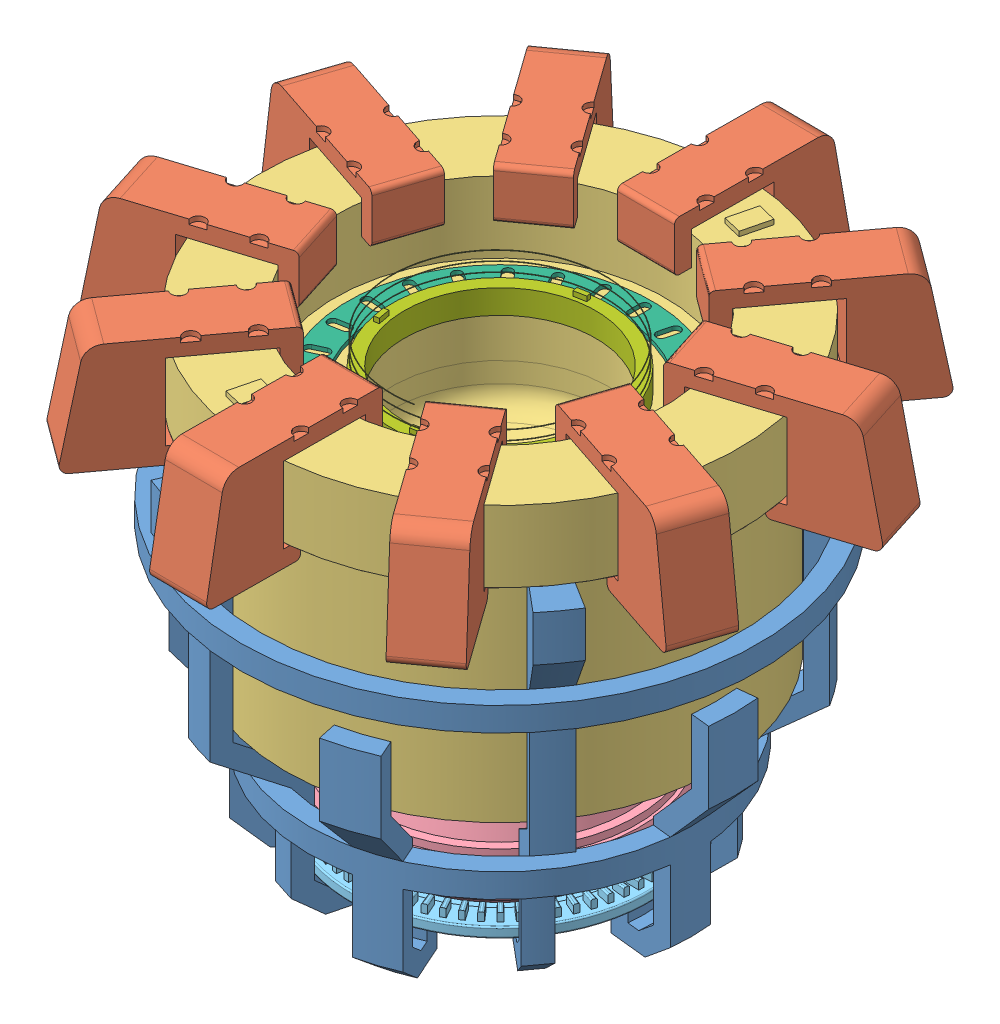
SolidWorks assembly TheArcReactor, configuration Default. Lengths in mm.
Overall size (168.05 102.8 166.25).
7 component instances, 7 part files, 16 mates.
Components (placement in the parent):
- Base-1: Base [Default] at origin size (133.9 83.07 126.71)
- ParticleAcceleratorModule-1: ParticleAcceleratorModule [Default] at (0 28.3999 0) x (-0.948876 0 -0.315649) z (0.315649 0 -0.948876) size (133.6 49.11 130.77)
- ReactonChamber-1: ReactonChamber [Default] at (0 -17.7 0) x (0.970296 0 0.241922) z (-0.241922 0 0.970296) size (99.78 62 99.78)
- ControlModule-1: ControlModule [Default] at (0 -37.5 0) x (-0.766044 0 0.642788) z (-0.642788 0 -0.766044) size (60 29.8 60)
- HeatSink-1: HeatSink [Default] at (0 -47.5 0) x (0.900552 0 -0.434748) z (0.434748 0 0.900552) size (62.2 4.49 62.2)
- TopCollar-1: TopCollar [Default] at (0 28.3 0) x (-0.766044 0 -0.642788) z (0.642788 0 -0.766044) size (63.54 0.85 63.54)
- Supporter-1: Supporter [Default] at (0 28.3 0) x (0.983571 0 -0.180519) z (0.180519 0 0.983571) size (47 11.05 46.2)
Mates (geometry in assembly coordinates):
- Concentric1: concentric aligned: cylinder of Base-1 through (0 15.0256 0) axis (0 1 0) radius 36; cylinder of HeatSink-1 through (0 202.4038 0) axis (0 1 0) radius 31.1
- Concentric5: concentric aligned: cylinder of Base-1 through (0 15.0256 0) axis (0 1 0) radius 50; cylinder of ReactonChamber-1 through (0 -112.8102 0) axis (0 1 0) radius 49.89
- Coincident17: coincident anti-aligned: circle of ParticleAcceleratorModule-1; circle of ReactonChamber-1
- Coincident18: coincident anti-aligned: plane of ReactonChamber-1 through (0 28.3 0) normal (0 1 0); plane of TopCollar-1 through (0 28.3 0) normal (0 -1 0)
- Concentric6: concentric anti-aligned: cylinder of ReactonChamber-1 through (0 -112.8102 0) axis (0 1 0) radius 34.5; cylinder of TopCollar-1 through (0 29.15 0) axis (0 -1 0) radius 31.77
- Tangent12: tangent anti-aligned: plane of Base-1 through (16.8846 -49 -14.1678) normal (0 1 0); torus of HeatSink-1
- Parallel9: parallel aligned: plane of ParticleAcceleratorModule-1 through (-31.5937 38.2999 -4.1866) normal (-0.315649 0 0.948876); plane of TopCollar-1 through (-28.1696 28.3 -10.4247) normal (-0.315649 0 0.948876)
- Concentric12: concentric aligned: cylinder of Base-1 through (0 15.0256 0) axis (0 1 0) radius 36; cone of ControlModule-1 through (0 -35.5 0) axis (0 1 0)
- Coincident32: coincident anti-aligned: plane of ControlModule-1 through (0 -47.5 0) normal (0 -1 0); plane of HeatSink-1 through (-23.0541 -47.5 11.1295) normal (0 1 0)
- Coincident33: coincident anti-aligned: plane of ReactonChamber-1 through (0 -17.7 0) normal (0 -1 0); plane of ControlModule-1 through (0 -17.7 0) normal (0 1 0)
- Parallel11: parallel aligned: plane of Base-1 through (0 0 0) normal (0.669131 0 0.743145); plane of HeatSink-1 through (0 -44.53 0) normal (0.669131 0 0.743145)
- Parallel14: parallel aligned: plane of Base-1 through (0 0 0) normal (-0.642788 0 -0.766044); plane of ControlModule-1 through (14.2951 -26.5 -13.3004) normal (-0.642788 0 -0.766044)
- Parallel17: parallel anti-aligned: plane of Base-1 through (0 0 0) normal (0.529919 0 0.848048); plane of TopCollar-1 through (25.9883 28.3 -15.0601) normal (-0.529919 0 -0.848048)
- Parallel19: parallel aligned: plane of Base-1 through (0 0 0) normal (0.970296 0 0.241922); plane of ReactonChamber-1 through (-7.7363 44.3 39.2957) normal (0.970296 0 0.241922)
- Coincident34: coincident aligned: circle of ReactonChamber-1; circle of Supporter-1
- Parallel20: parallel aligned: plane of TopCollar-1 through (-29.7073 28.3 4.4356) normal (0.180519 0 0.983571); plane of Supporter-1 through (-20.2326 34.3 4.9843) normal (0.180519 0 0.983571)
